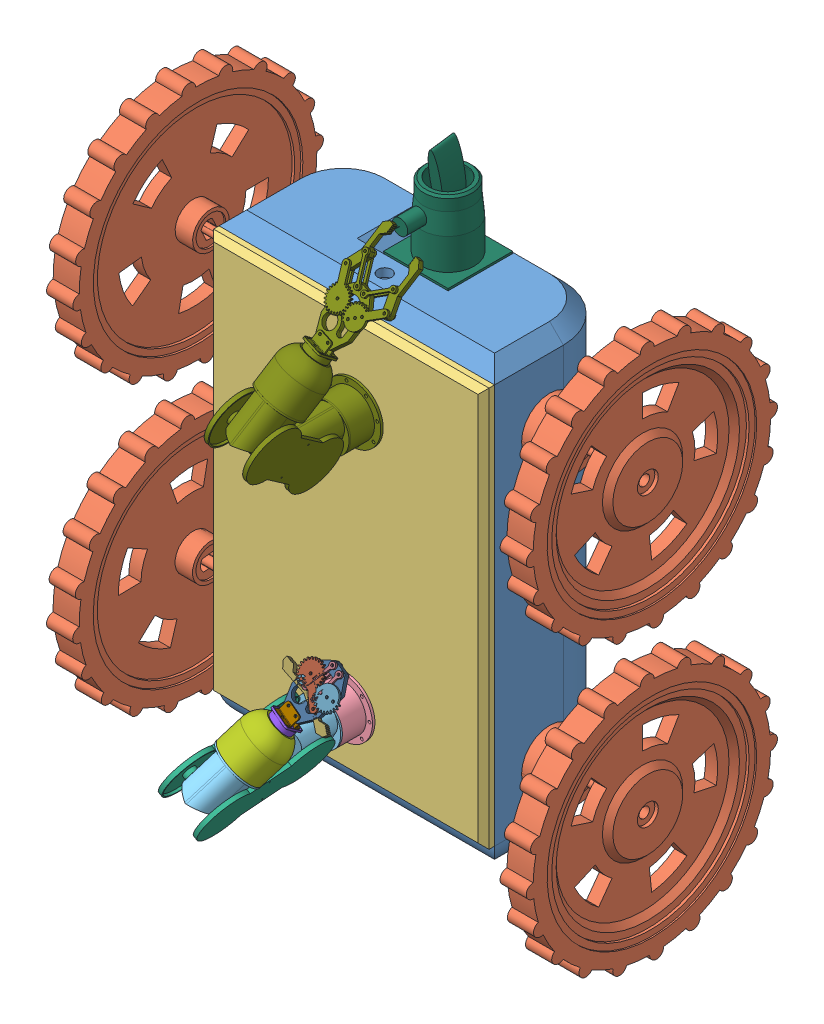
SolidWorks assembly final assem, configuration Default. Lengths in mm.
Overall size (174.23 220.88 143.34).
32 component instances, 16 part files, 18 mates.
Components (placement in the parent):
- body mon 1-1: body mon 1 [Default] at origin size (100 160 45)
- Assem8-1: Assem8 [Standard] at (-6.8046 40.7747 8.5592) x (0 -0.419147 0.907919) z (-1 0 0) size (91.19 91.19 67.11)
- Assem8-2: Assem8 [Standard] at (-6.8046 -40.5649 8.2727) x (0 0.992121 0.125282) z (-1 0 0) size (91.19 91.19 67.11)
- Assem8-3: Assem8 [Standard] at (6.8046 -58.9513 -12.5454) x (0 0 -1) z (1 0 0) size (91.19 91.19 67.11)
- Assem8-4: Assem8 [Standard] at (6.8046 45.443 -12.5454) x (0 0 -1) z (1 0 0) size (91.19 91.19 67.11)
- led-1: led [Default] at (0 2.5 20) x (0 1 0) z (1 0 0) size (145 4 100)
- Assemmbled robot Arm-1: Assemmbled robot Arm [Default] at (-27.0437 9.7116 4.4145) x (1 0 0) z (0 -1 0) size (40.26 58.81 52.31)
  - Base-1: Base [Default] at (27.0827 13.4791 58.5156) size (21.09 9.51 21.09)
  - Hombro-2: Hombro [Default] at (27.0827 12.4192 58.5156) x (0.865116 0 0.501572) z (-0.501572 0 0.865116) size (16.5 16.41 16.5)
  - Lateral-1: Lateral [Default] at (17.6192 53.9923 56.6658) x (0.118878 -0.971507 -0.205042) z (-0.487281 -0.237011 0.840466) size (45.6 2.4 19.05)
  - Lateral-2: Lateral [Default] at (33.39 53.9923 65.8093) x (-0.118878 0.971507 0.205042) z (-0.487281 -0.237011 0.840466) size (45.6 2.4 19.05)
  - Hombro-3: Hombro [Default] at (35.7251 50.4883 43.609) x (0.865116 0 0.501572) z (-0.286862 -0.820306 0.494781) size (16.5 16.41 16.5)
  - Rotor-1: Rotor [Default] at (21.4812 70.2882 68.1772) x (0.200423 0.816332 -0.541694) z (-0.889126 -0.080644 -0.450501) size (16.5 15.24 16.5)
  - Arm 01-1: Arm 01 [Default] at (36.844 48.9331 41.6792) x (-0.087481 -0.799803 0.593854) z (0.907228 0.182255 0.379106) size (8.38 2.59 8.32)
  - Arm 02-2: Arm 02 [Default] at (35.4716 51.6503 43.6573) x (-0.907228 -0.182255 -0.379106) z (0.411443 -0.571925 -0.70966) size (6 3 4.2)
  - Arm 02-3: Arm 02 [Default] at (35.3179 50.245 44.7007) x (0.907228 0.182255 0.379106) z (0.411443 -0.571925 -0.70966) size (6 3 4.2)
  - Arm 03-1: Arm 03 [Default] at (43.0818 39.6 30.786) x (-0.907228 -0.182255 -0.379106) z (-0.411443 0.571925 0.70966) size (12.3 0.9 18.6)
  - Arm 03-2: Arm 03 [Default] at (43.1605 40.3198 30.2515) x (-0.907228 -0.182255 -0.379106) z (-0.411443 0.571925 0.70966) size (12.3 0.9 18.6)
  - Arm 04-1: Arm 04 [Default] at (36.2687 41.7733 29.6784) x (0.555057 0.455888 0.695757) z (-0.827199 0.390488 0.404055) size (14.86 0.9 8.72)
  - Arm 07-1: Arm 07 [Default] at (48.8548 45.9306 40.1625) x (0.087481 0.799803 -0.593854) z (0.7649 0.327978 0.554399) size (0.9 6.45 18)
  - Arm 07-4: Arm 07 [Default] at (48.9336 46.6504 39.628) x (0.087481 0.799803 -0.593854) z (0.7649 0.327978 0.554399) size (0.9 6.45 18)
  - Arm 07-7: Arm 07 [Default] at (32.4052 40.2677 30.1126) x (-0.087481 -0.799803 0.593854) z (-0.894198 -0.199689 -0.400667) size (0.9 6.45 18)
  - Arm 07-9: Arm 07 [Default] at (32.4839 40.9876 29.5782) x (-0.087481 -0.799803 0.593854) z (-0.894198 -0.199689 -0.400667) size (0.9 6.45 18)
  - Arm 06-1: Arm 06 [Default] at (43.7246 43.0741 32.5287) x (0.385834 -0.576812 -0.720014) z (-0.918411 -0.166142 -0.359051) size (11.4 0.9 2.1)
  - Arm 06-2: Arm 06 [Default] at (40.3364 42.3795 31.094) x (-0.499898 0.550889 0.668298) z (0.861655 0.238403 0.448012) size (11.4 0.9 2.1)
  - Arm 06-3: Arm 06 [Default] at (43.4884 40.9147 34.1321) x (0.385834 -0.576812 -0.720014) z (-0.918411 -0.166142 -0.359051) size (11.4 0.9 2.1)
  - Arm 06-4: Arm 06 [Default] at (40.1002 40.22 32.6974) x (-0.499898 0.550889 0.668298) z (0.861655 0.238403 0.448012) size (11.4 0.9 2.1)
  - Arm 06-6: Arm 06 [Default] at (40.243 42.8264 36.2288) x (0.555057 0.455888 0.695757) z (0.827199 -0.390488 -0.404055) size (11.4 0.9 2.1)
  - Arm 06-7: Arm 06 [Default] at (40.4016 42.2308 35.45) x (0.991183 -0.01033 0.132098) z (0.099518 -0.600173 -0.793655) size (11.4 0.9 2.1)
  - Arm 05-4: Arm 05 [Default] at (49.3754 44.0774 34.7123) x (0.953817 -0.239221 -0.181676) z (-0.287367 -0.550535 -0.783793) size (13.88 0.9 9.12)
- Propeller final-1: Propeller final [Default] at (-15.6453 47.4609 -12.1582) x (1 0 0) z (0 -1 0) size (23.46 45.24 153.84)
- Assemmbled robot Arm 1-1: Assemmbled robot Arm 1 [Default] at (-35.3273 96.9993 4.4145) x (0.979209 0.202853 0) z (0.202853 -0.979209 0) size (55.56 51.6 77.34)
Mates (geometry in assembly coordinates):
- Coincident1: coincident anti-aligned: plane of body mon 1-1 through (-20 52.1653 0) normal (-1 0 0); plane of Assem8-1 through (-20 57.8083 0.8153) normal (1 0 0)
- Concentric1: concentric anti-aligned: cylinder of body mon 1-1 through (-20 52.1653 0) axis (-1 0 0) radius 10.2; cylinder of Assem8-1 through (-60.2996 52.1653 0) axis (1 0 0) radius 9.8637
- Coincident2: coincident anti-aligned: plane of body mon 1-1 through (-20 -52.1653 0) normal (-1 0 0); plane of Assem8-2 through (-20 -53.0928 -5.6256) normal (1 0 0)
- Concentric2: concentric anti-aligned: cylinder of body mon 1-1 through (-20 -52.1653 0) axis (-1 0 0) radius 10.2; cylinder of Assem8-2 through (-60.2996 -52.1653 0) axis (1 0 0) radius 9.8637
- Coincident3: coincident anti-aligned: plane of body mon 1-1 through (20 -52.1971 0) normal (1 0 0); plane of Assem8-3 through (20 -46.732 1.625) normal (-1 0 0)
- Concentric3: concentric anti-aligned: cylinder of body mon 1-1 through (20 -52.1971 0) axis (1 0 0) radius 10.2; cylinder of Assem8-3 through (60.2996 -52.1971 0) axis (-1 0 0) radius 9.8637
- Coincident4: coincident anti-aligned: plane of body mon 1-1 through (20 52.1971 0) normal (1 0 0); plane of Assem8-4 through (20 57.6622 1.625) normal (-1 0 0)
- Concentric4: concentric anti-aligned: cylinder of body mon 1-1 through (20 52.1971 0) axis (1 0 0) radius 10.2; cylinder of Assem8-4 through (60.2996 52.1971 0) axis (-1 0 0) radius 9.8637
- Coincident15: coincident aligned: line of body mon 1-1 through (50 75 20) axis (-1 0 0); line of led-1 through (50 75 20) axis (-1 0 0)
- Coincident16: coincident aligned: line of body mon 1-1 through (-50 75 20) axis (0 -1 0); line of led-1 through (-50 75 20) axis (0 -1 0)
- Parallel7: parallel anti-aligned: plane of led-1 through (0 2.5 24) normal (0 0 1); plane of Assemmbled robot Arm-1/Base-1 through (0.039 -48.8041 24) normal (0 0 -1)
- Coincident22: coincident aligned: plane of led-1 through (0 2.5 24) normal (0 0 1); circle of Assemmbled robot Arm-1/Base-1
- Coincident23: coincident anti-aligned: line of body mon 1-1 through (12 75 -1.1277) axis (0 0 -1); line of Propeller final-1 through (12 75 -23.1078) axis (0 0 1)
- Coincident24: coincident anti-aligned: line of body mon 1-1 through (-11 75 -1.1277) axis (1 0 0); line of Propeller final-1 through (12 75 -1.1277) axis (-1 0 0)
- Coincident25: coincident aligned: plane of led-1 through (0 2.5 24) normal (0 0 1); circle of Assemmbled robot Arm-1/Base-1
- Coincident26: coincident anti-aligned: plane of led-1 through (0 2.5 24) normal (0 0 1); plane of Assemmbled robot Arm 1-1 through (3.0623 45.1941 24) normal (0 0 -1)
- Lock1: lock: unknown of led-1; unknown of Assemmbled robot Arm-1/Base-1
- Lock2: lock: unknown of led-1; unknown of Assemmbled robot Arm 1-1
